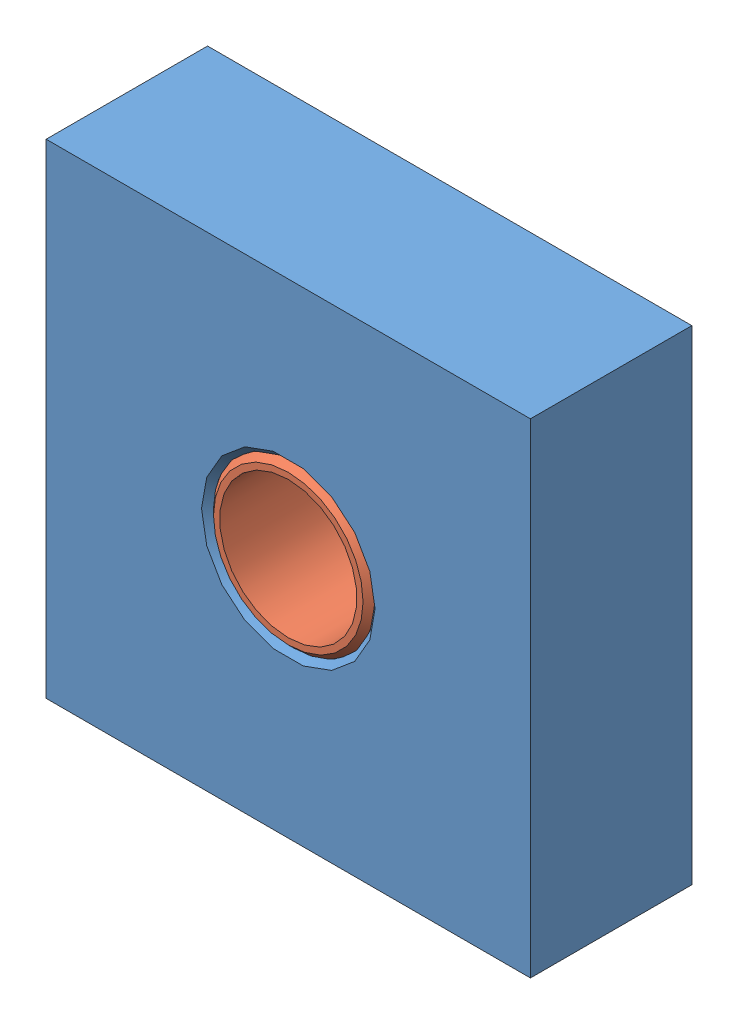
SolidWorks assembly Bushing and Frame 5-1, configuration Default. Lengths in mm.
Overall size (120 120 40).
2 component instances, 2 part files, 2 mates.
Components (placement in the parent):
- Frame-1: Frame [Default] at origin size (120 120 40)
- Bushing-2: Bushing [Default] x (1 0 0) z (0 1 0) size (40.06 40 40.06)
Mates (geometry in assembly coordinates):
- Concentric1: concentric anti-aligned: cylinder of Frame-1 through (0 0 20) axis (0 0 -1) radius 20; cylinder of Bushing-2 through (0 0 -20) axis (0 0 1) radius 20.032
- Coincident1: coincident aligned: plane of Frame-1 through (-60 -60 20) normal (0 0 1); plane of Bushing-2 through (0 0 20) normal (0 0 1)
